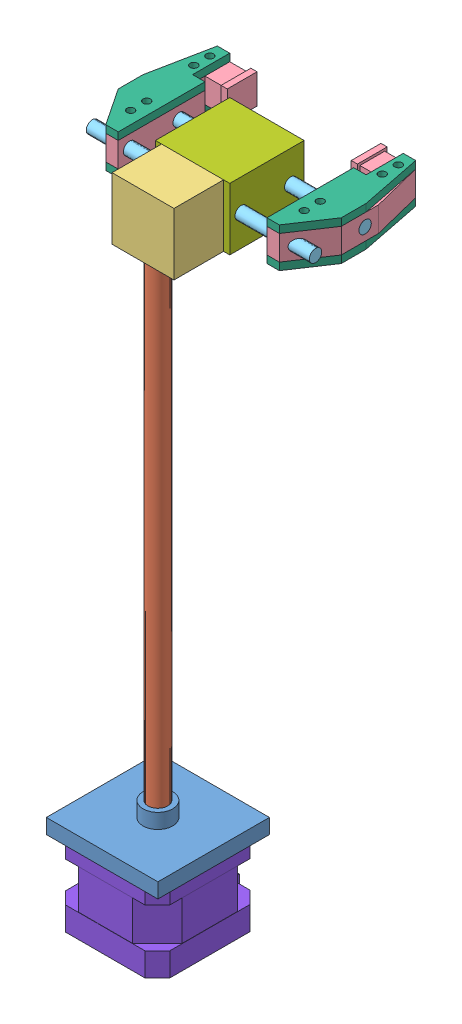
SolidWorks assembly Ensamblaje_Link3.2, configuration Predeterminado. Lengths in mm.
Overall size (90 259.5 87.5).
14 component instances, 8 part files, 14 mates.
Components (placement in the parent):
- Pieza8-1: Pieza8 [Predeterminado] at origin size (45 12 45)
- Pieza6-1: Pieza6 [Predeterminado] at (0 6 0) size (8 215 8)
- Pieza7-1: Pieza7 [Predeterminado] at (0 215.5 -14) x (0 1 0) z (1 0 0) size (25 20 25)
- Gripper-1: Gripper [Predeterminado] at (0 203 -29) x (-1 0 0) z (0 1 0) size (90 58 25)
  - Pieza12-1: Pieza12 [Predeterminado] at (-35 -35 7.5) size (20 51 12)
  - Pieza12-2: Pieza12 [Predeterminado] at (35 -35 17.5) x (-1 0 0) z (0 0 -1) size (20 51 12)
  - Pieza13-1: Pieza13 [Predeterminado] at (-45 10.4 12.5) x (1 0 0) z (0 0.910954 0.412508) size (90 5 5)
  - Pieza13-2: Pieza13 [Predeterminado] at (-45 -9.6 12.5) x (1 0 0) z (0 0.999804 -0.019809) size (90 5 5)
  - Pieza11-1: Pieza11 [Predeterminado] at (-35 -35 17.5) size (15 50 3)
  - Pieza11-2: Pieza11 [Predeterminado] at (-35 -35 4.5) size (15 50 3)
  - Pieza11-3: Pieza11 [Predeterminado] at (35 -35 7.5) x (-1 0 0) z (0 0 -1) size (15 50 3)
  - Pieza11-4: Pieza11 [Predeterminado] at (35 -35 20.5) x (-1 0 0) z (0 0 -1) size (15 50 3)
  - Pieza14-1: Pieza14 [Predeterminado] at origin size (30 37 25)
- Motor Paso a Paso-1: Motor Paso a Paso [Predeterminado] at (0 -31.5 0) x (-1 0 0) z (0 0 -1) size (42 55.2 46)
Mates (geometry in assembly coordinates):
- Coincidente4: coincident aligned: plane of Pieza8-1 through (0 0 0) normal (0 0 1)
- Coincidente5: coincident aligned: plane of Pieza8-1 through (0 0 0) normal (0 1 0)
- Coincidente6: coincident aligned: plane of Pieza8-1 through (0 0 0) normal (1 0 0)
- Concéntrica2: concentric aligned: cylinder of Pieza8-1 through (0 12 0) axis (0 -1 0) radius 4; cylinder of Pieza6-1 through (0 221 0) axis (0 -1 0) radius 4
- Coincidente7: coincident anti-aligned: plane of Pieza8-1 through (0 6 0) normal (0 1 0); plane of Pieza6-1 through (0 6 0) normal (0 -1 0)
- Concéntrica3: concentric aligned: cylinder of Pieza6-1 through (0 221 0) axis (0 -1 0) radius 4; cylinder of Pieza7-1 through (0 221 0) axis (0 -1 0) radius 4
- Paralelo1: parallel aligned: plane of Pieza8-1 through (-22.5 6 22.5) normal (0 0 1); plane of Pieza7-1 through (0 215.5 6) normal (0 0 1)
- Coincidente9: coincident anti-aligned: plane of Pieza6-1 through (0 221 0) normal (0 1 0); plane of Pieza7-1 through (0 221 0) normal (0 -1 0)
- Concéntrica5: concentric aligned: cylinder of Pieza7-1 through (0 215.5 -7) axis (0 0 -1) radius 10; cylinder of Gripper-1/Pieza14-1 through (0 215.5 -7) axis (0 0 -1) radius 10
- Coincidente10: coincident anti-aligned: plane of Pieza7-1 through (0 215.5 -7) normal (0 0 -1); plane of Gripper-1/Pieza14-1 through (0 215.5 -7) normal (0 0 1)
- Coincidente11: coincident aligned: plane of Pieza7-1 through (12.5 228 6) normal (0 1 0); plane of Gripper-1/Pieza14-1 through (0 228 -29) normal (0 1 0)
- Coincidente12: coincident anti-aligned: plane of Pieza8-1 through (-21 1.7 -21.2) normal (0 0 1); plane of Motor Paso a Paso-1 through (16 1.7 -21.2) normal (0 0 -1)
- Coincidente13: coincident anti-aligned: plane of Pieza8-1 through (0 1.7 0) normal (0 -1 0); plane of Motor Paso a Paso-1 through (0 1.7 0) normal (0 1 0)
- Coincidente14: coincident anti-aligned: plane of Pieza8-1 through (21 1.7 -21.2) normal (-1 0 0); plane of Motor Paso a Paso-1 through (21 1.7 16.2) normal (1 0 0)
